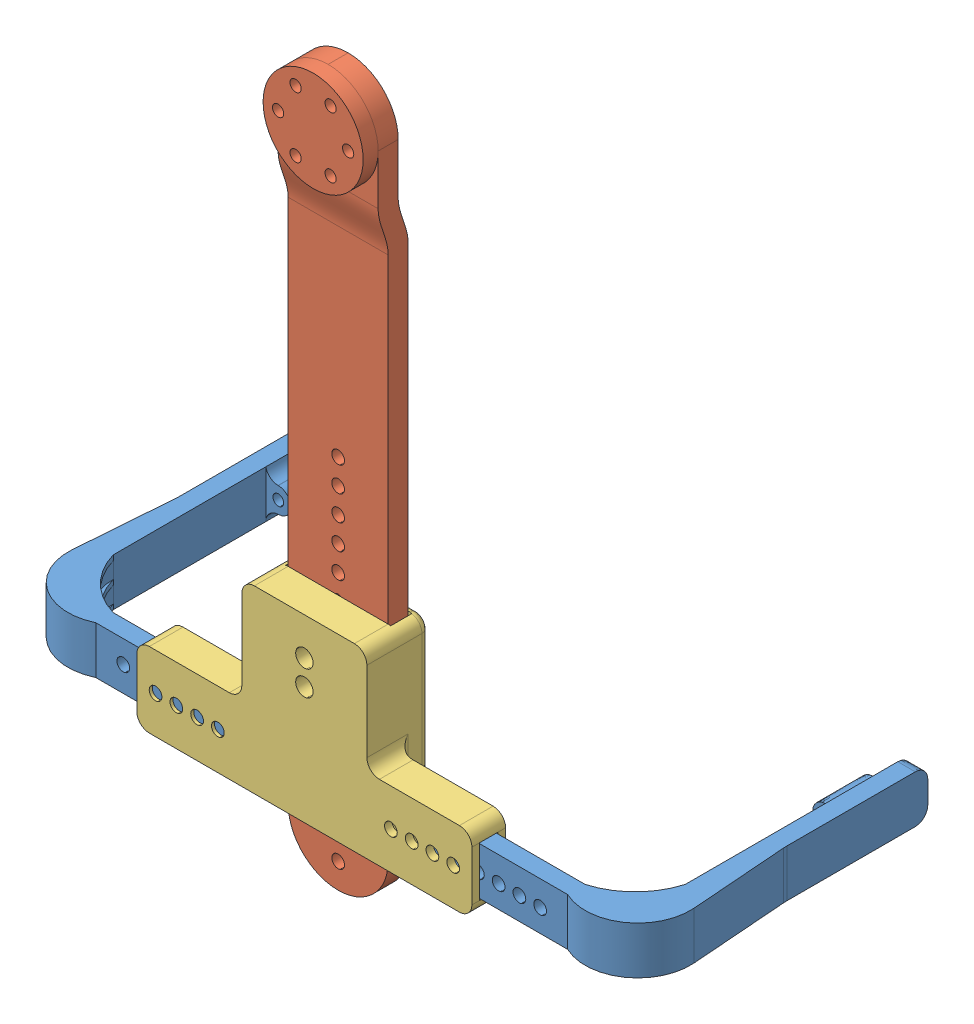
SolidWorks assembly Running_exo_edits_June_7th_2024, configuration Default. Lengths in mm.
Overall size (246.8 288 122.02).
4 component instances, 3 part files, 5 mates.
Components (placement in the parent):
- Lshape-thigh_running-2: Lshape-thigh_running [Default] at (228.4673 132.3241 18.8806) x (0 0 1) z (-1 0 0) size (120 19 90.06)
- Lshape-thigh_running-3: Lshape-thigh_running [Default] at (-12.207 153.1197 20.9009) x (0 0 1) z (1 0 0) size (120 19 90.06)
- RotorAttachCanted_vertical-2: RotorAttachCanted_vertical [Default] at (98.9386 364.1605 135.1306) x (-1 0 0) z (0 0 -1) size (60 288 18)
- ThighTShape_v3-2: ThighTShape_v3 [Default] at (99.4386 162.8241 139.1306) x (-1 0 0) z (0 0 -1) size (134 72 25)
Mates (geometry in assembly coordinates):
- Parallel8: parallel anti-aligned: plane of RotorAttachCanted_vertical-2 through (118.9386 96.1605 125.1306) normal (0 0 1); plane of ThighTShape_v3-2 through (120.4386 126.8241 125.6306) normal (0 0 -1)
- Distance14: distance = 0.5 mm anti-aligned: plane of ThighTShape_v3-2 through (78.4386 126.8241 125.6306) normal (1 0 0); plane of RotorAttachCanted_vertical-2 through (78.9386 384.1605 121.1306) normal (-1 0 0)
- Distance15: distance = 0.5 mm anti-aligned: plane of RotorAttachCanted_vertical-2 through (118.9386 96.1605 125.1306) normal (0 0 1); plane of ThighTShape_v3-2 through (120.4386 126.8241 125.6306) normal (0 0 -1)
- Distance16: distance = 0.25 mm anti-aligned: plane of ThighTShape_v3-2 through (75.9386 151.8241 128.6306) normal (0 0 1); plane of Lshape-thigh_running-2 through (201.4673 151.3241 128.8806) normal (0 0 -1)
- Distance17: distance = 0.5 mm anti-aligned: plane of ThighTShape_v3-2 through (75.9386 151.8241 136.1306) normal (0 -1 0); plane of Lshape-thigh_running-2 through (201.4673 151.3241 108.8806) normal (0 1 0)
